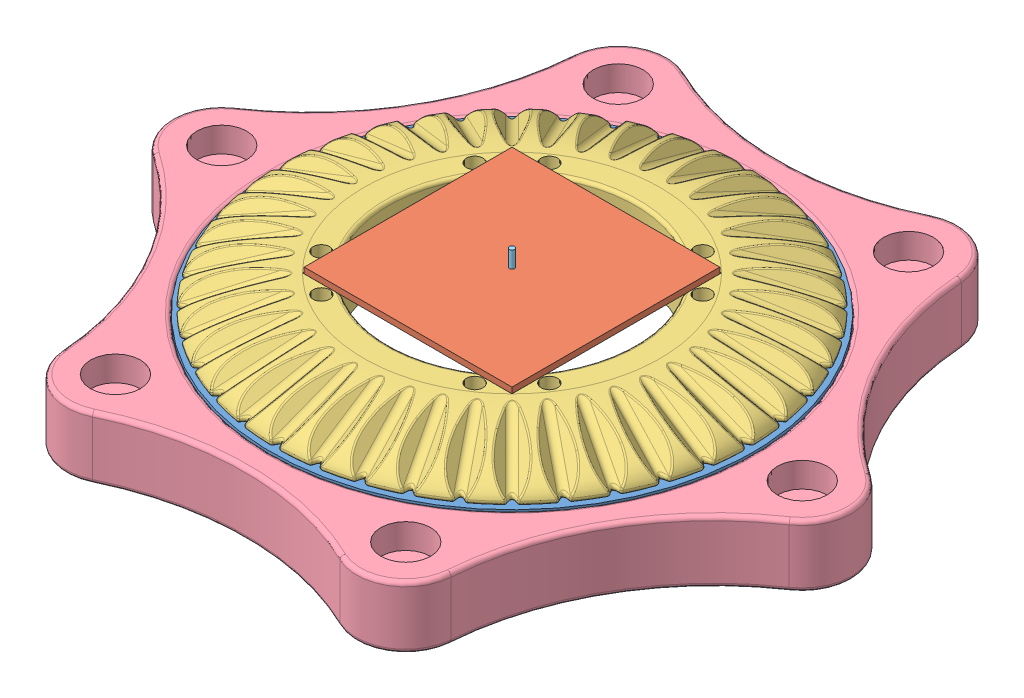
SolidWorks assembly Eyeglass holder, configuration Default. Lengths in mm.
Overall size (81.7 14.28 72.34).
8 component instances, 8 part files, 13 mates.
Components (placement in the parent):
- Bearing 45_58_7mm-1: Bearing 45_58_7mm [Default] x (1 0 0) z (0 1 0) size (58 58 7)
- Glass Slide-1: Glass Slide [Default] at (0 7.933 0) size (25 0.7 25)
- Dial^Eyeglass holder-1: Dial^Eyeglass holder [Default] at origin size (57.05 8.47 57.05) (virtual)
- Part5^Eyeglass holder-1: Part5^Eyeglass holder [Default] at origin size (80.18 8.26 64.35) (hidden, virtual)
- slider for glass-1: slider for glass [Default] at (43.8806 -0.3725 0) x (0.558674 -0.829387 0) z (-0.829387 -0.558674 0) size (29.05 6.4 50.8) (hidden)
- Part1^Eyeglass holder-1: Part1^Eyeglass holder [Default] at origin size (81.7 7.5 72.34) (virtual)
- statue-1: statue [Default] at (0 9.283 0) size (0.62 2 0.62)
- slide_clip-1: slide_clip [Default] at (-11.4689 8.283 -11.4689) x (-0.707107 0 0.707107) z (-0.707107 0 -0.707107) size (10.35 2 4) (hidden)
Mates (geometry in assembly coordinates):
- Coincident1: coincident anti-aligned: line of Bearing 45_58_7mm-1 through (7 0 3.5) axis (0 0 -1)
- Coincident2: coincident: point of Bearing 45_58_7mm-1
- Coincident3: coincident aligned: plane of Bearing 45_58_7mm-1 through (0 0 0) normal (1 0 0)
- Coincident4: coincident: unknown of Glass Slide-1
- Coincident6: coincident aligned: plane of Glass Slide-1 through (0 7.933 0) normal (0 0 1)
- Coincident7: coincident aligned: plane of slider for glass-1 through (43.8806 -0.3725 0) normal (0 0 1)
- Concentric1: concentric anti-aligned: cylinder of Part5^Eyeglass holder-1 through (43.8806 -0.3725 -14.4895) axis (0 0 1) radius 1.5875; cylinder of slider for glass-1 through (43.8806 -0.3725 3.175) axis (0 0 -1) radius 1.27
- Distance2: distance = 0.508 mm anti-aligned: plane of Glass Slide-1 through (0 7.583 0) normal (0 -1 0); plane of Dial^Eyeglass holder-1 through (0 7.075 0) normal (0 1 0)
- Coincident9: coincident anti-aligned: plane of Glass Slide-1 through (0 8.283 0) normal (0 1 0); plane of statue-1 through (0 8.283 0) normal (0 -1 0)
- Coincident10: coincident: unknown of statue-1
- Concentric2: concentric anti-aligned: cylinder of Dial^Eyeglass holder-1 through (-9.2238 4.5 -13.714) axis (0 1 0) radius 1; cylinder of slide_clip-1 through (-9.2238 10.283 -13.714) axis (0 -1 0) radius 1
- Concentric3: concentric anti-aligned: cylinder of Dial^Eyeglass holder-1 through (-13.714 4.5 -9.2238) axis (0 1 0) radius 1; cylinder of slide_clip-1 through (-13.714 10.283 -9.2238) axis (0 -1 0) radius 1
- Coincident11: coincident anti-aligned: plane of Glass Slide-1 through (0 8.283 0) normal (0 1 0); plane of slide_clip-1 through (-9.2238 8.283 -13.714) normal (0 -1 0)
